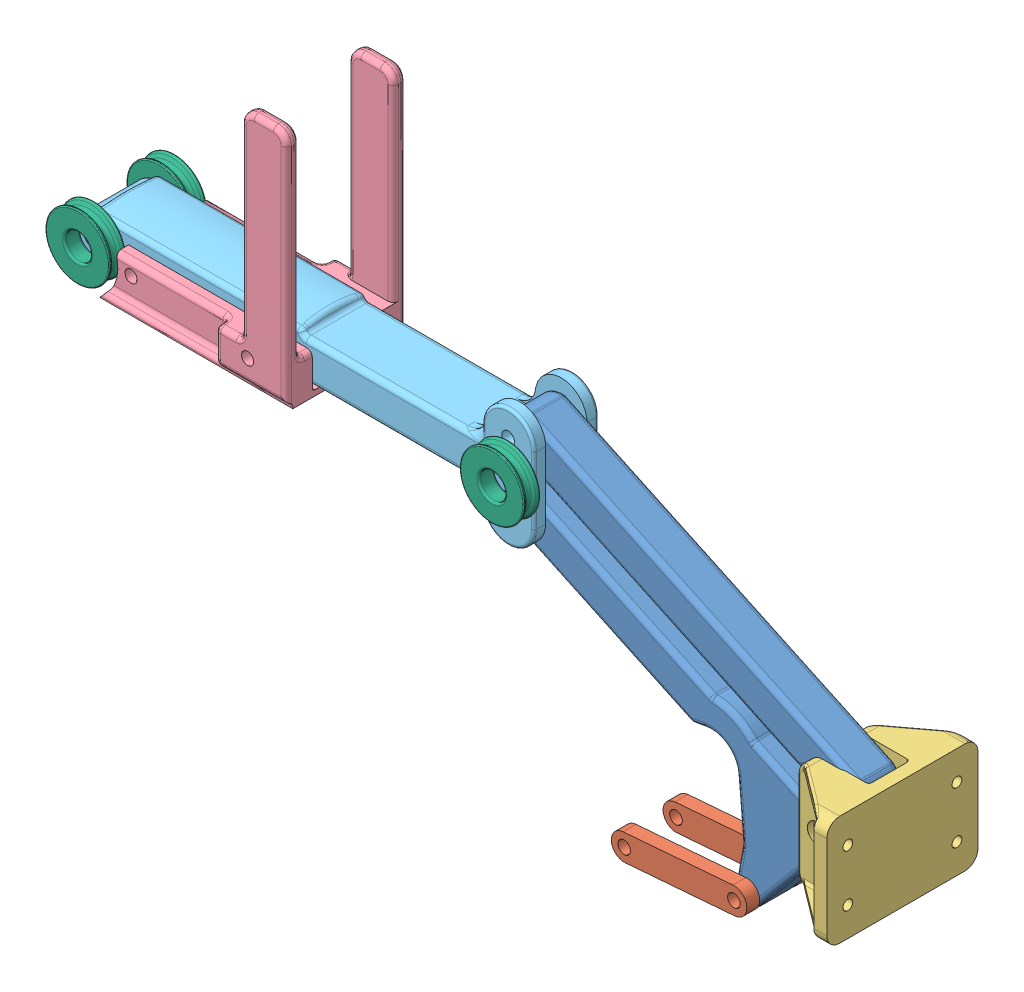
SolidWorks assembly grasper assembly, configuration Default. Lengths in mm.
Overall size (395.8 253.74 74.17).
11 component instances, 7 part files, 34 mates.
Components (placement in the parent):
- arm link-2: arm link [5] at (-109.0843 168.5123 1.2065) x (-0.905616 0.424098 0) z (0 0 -1) size (197.05 24.13 19.05)
- arm link-3: arm link [Default] at (-109.0843 135.4923 0.5715) x (-0.905616 0.424098 0) z (0 0 1) size (197.05 71.69 19.05)
- link driver-2: link driver [Default] at (-105.7742 63.1 13.2715) x (0.996822 0.079659 0) z (0 0 1) size (66.67 12.7 6.35)
- Mounting Bracket-1: Mounting Bracket [Default] at (-12.7 141.2875 0) x (0 0 1) z (0 -1 0) size (74.17 34.92 53.98)
- link driver-3: link driver [Default] at (-105.7742 63.1 -12.1285) x (0.996822 0.079659 0) z (0 0 1) size (66.67 12.7 6.35)
- gutter-1: gutter [Default] at (-303.8936 189.7046 -22.4155) x (-1 0 0) z (0 0 1) size (94.64 118.27 58.79)
- Plate Holder-1: Plate Holder [Default] at (-373.7436 180.1796 17.3169) size (85.72 114.3 6.35) (hidden)
- Contact Arm-2: Contact Arm [Default] at (-189.5936 173.1946 16.4465) x (-1 0 0) z (0 0 -1) size (225.43 58.42 31.75)
- End Pulley-1: End Pulley [Default] at (-392.7936 189.7046 20.4465) size (31.4 31.4 8)
- End Pulley-2: End Pulley [Default] at (-392.7936 189.7046 -19.3035) size (31.4 31.4 8)
- End Pulley-3: End Pulley [Default] at (-189.5936 189.7046 20.4465) x (0.954377 0.298605 0) z (0 0 1) size (31.4 31.4 8)
Mates (geometry in assembly coordinates):
- Coincident5: coincident: plane of ? through (0 0 0) normal (1 0 0); plane of assembly through (0 0 0) normal (1 0 0)
- Coincident6: coincident: plane of ? through (0 0 0) normal (0 1 0); plane of assembly through (0 0 0) normal (0 1 0)
- Coincident7: coincident: plane of ? through (0 0 0) normal (0 0 1); plane of assembly through (0 0 0) normal (0 0 1)
- Coincident8: coincident: point of ?; line of ? through (27.94 13.97 0) axis (0 -1 0)
- Concentric5: concentric: cylinder of ? through (-12.7 0 0) axis (1 0 0) radius 6.35; cylinder of ? through (-140.462 0 0) axis (-1 0 0) radius 6.35
- Coincident12: coincident: plane of ? through (-12.7 0 0) normal (-1 0 0); plane of ? through (-12.7 0 0) normal (1 0 0)
- Distance5: distance = 50.8 mm: sphere of ?; plane of ? through (-153.162 0 0) normal (-1 0 0)
- Distance8: distance = 63.5 mm: cylinder of link driver-2 through (-134.2367 63.5 16.4465) axis (0 0 -1) radius 3.1115; line of ? through (27.94 13.97 0) axis (0 -1 0)
- Coincident25: coincident: plane of ? through (-12.7 0 0) normal (-1 0 0); plane of Mounting Bracket-1 through (-12.7 87.3125 -37.084) normal (1 0 0)
- Coincident26: coincident: plane of ? through (0 0 0) normal (0 0 1); plane of Mounting Bracket-1 through (-12.7 141.2875 0) normal (0 0 1)
- Distance9: distance = 114.3 mm: cylinder of Mounting Bracket-1 through (-38.1 114.3 37.084) axis (0 0 -1) radius 3.9688; cylinder of ? through (-12.7 0 0) axis (1 0 0) radius 6.35
- Concentric16: concentric: cylinder of arm link-3 through (-28.575 97.79 10.0965) axis (0 0 -1) radius 3.1115; cylinder of Mounting Bracket-1 through (-28.575 97.79 37.084) axis (0 0 -1) radius 3.175
- Coincident27: coincident: plane of arm link-3 through (-109.0843 135.4923 10.0965) normal (0 0 1); plane of Mounting Bracket-1 through (-47.625 87.3125 10.0965) normal (0 0 -1)
- Concentric19: concentric: cylinder of link driver-2 through (-78.8725 65.2498 16.4465) axis (0 0 -1) radius 3.1115; cylinder of arm link-3 through (-78.8725 65.2498 10.0965) axis (0 0 -1) radius 3.1115
- Coincident29: coincident: plane of arm link-3 through (-109.0843 135.4923 10.0965) normal (0 0 1); plane of link driver-2 through (-132.676 60.9502 10.0965) normal (0 0 -1)
- Concentric22: concentric: cylinder of link driver-3 through (-78.8725 65.2498 -8.9535) axis (0 0 -1) radius 3.1115; cylinder of arm link-3 through (-78.8725 65.2498 10.0965) axis (0 0 -1) radius 3.1115
- Coincident31: coincident: plane of arm link-3 through (-109.0843 135.4923 -8.9535) normal (0 0 -1); plane of link driver-3 through (-132.676 60.9502 -8.9535) normal (0 0 1)
- Concentric23: concentric: cylinder of link driver-2 through (-132.676 60.9502 16.4465) axis (0 0 -1) radius 3.1115; cylinder of link driver-3 through (-132.676 60.9502 -8.9535) axis (0 0 -1) radius 3.1115
- Concentric30: concentric: cylinder of arm link-3 through (-189.5936 173.1946 10.0965) axis (0 0 -1) radius 3.1115; cylinder of Contact Arm-2 through (-189.5936 173.1946 -15.3035) axis (0 0 1) radius 3.1115
- Width1: width: plane of Contact Arm-2 through (-202.2936 173.1946 10.7315) normal (0 0 -1); plane of Contact Arm-2 through (-202.2936 173.1946 -9.5885) normal (0 0 1); plane of arm link-3 through (-109.0843 135.4923 10.0965) normal (0 0 1); plane of arm link-3 through (-109.0843 135.4923 -8.9535) normal (0 0 -1)
- Concentric32: concentric: cylinder of Plate Holder-1 through (-367.3936 189.7046 23.6669) axis (0 0 -1) radius 3.175; cylinder of Contact Arm-2 through (-367.3936 189.7046 16.4465) axis (0 0 -1) radius 3.1115
- Concentric33: concentric: cylinder of Plate Holder-1 through (-303.8936 189.7046 23.6669) axis (0 0 -1) radius 3.175; cylinder of Contact Arm-2 through (-303.8936 189.7046 16.4465) axis (0 0 -1) radius 3.1115
- Concentric34: concentric: cylinder of gutter-1 through (-303.8936 189.7046 23.5585) axis (0 0 -1) radius 3.048; cylinder of Contact Arm-2 through (-303.8936 189.7046 16.4465) axis (0 0 -1) radius 3.1115
- Concentric35: concentric: cylinder of gutter-1 through (-367.3936 189.7046 23.5585) axis (0 0 -1) radius 3.048; cylinder of Contact Arm-2 through (-367.3936 189.7046 16.4465) axis (0 0 -1) radius 3.1115
- Width3: width: plane of gutter-1 through (-379.5238 189.7046 -16.0655) normal (0 0 1); plane of gutter-1 through (-379.5238 189.7046 17.2085) normal (0 0 -1); plane of Contact Arm-2 through (-189.5936 173.1946 -15.3035) normal (0 0 -1); plane of Contact Arm-2 through (-189.5936 173.1946 16.4465) normal (0 0 1)
- Concentric36: concentric: cylinder of Contact Arm-2 through (-392.7936 189.7046 13.2715) axis (0 0 1) radius 4.7625; cylinder of End Pulley-1 through (-392.7936 189.7046 16.4465) axis (0 0 1) radius 6.35
- Coincident35: coincident: plane of Contact Arm-2 through (-189.5936 173.1946 16.4465) normal (0 0 1); plane of End Pulley-1 through (-392.7936 189.7046 16.4465) normal (0 0 -1)
- Concentric37: concentric: cylinder of Contact Arm-2 through (-392.7936 189.7046 -12.1285) axis (0 0 -1) radius 4.7625; cylinder of End Pulley-2 through (-392.7936 189.7046 -23.3035) axis (0 0 1) radius 6.35
- Coincident36: coincident: plane of Contact Arm-2 through (-189.5936 173.1946 -15.3035) normal (0 0 -1); plane of End Pulley-2 through (-392.7936 189.7046 -15.3035) normal (0 0 1)
- Concentric38: concentric: cylinder of Contact Arm-2 through (-189.5936 189.7046 -15.3035) axis (0 0 1) radius 3.1115; cylinder of End Pulley-3 through (-189.5936 189.7046 16.4465) axis (0 0 1) radius 6.35
- Coincident37: coincident: plane of Contact Arm-2 through (-189.5936 173.1946 16.4465) normal (0 0 1); plane of End Pulley-3 through (-189.5936 189.7046 16.4465) normal (0 0 -1)
- Concentric39: concentric: cylinder of arm link-2 through (-28.575 130.81 -8.3185) axis (0 0 1) radius 3.1115; cylinder of Mounting Bracket-1 through (-28.575 130.81 37.084) axis (0 0 -1) radius 3.175
- Concentric40: concentric: cylinder of arm link-2 through (-189.5936 206.2146 -8.3185) axis (0 0 1) radius 3.1115; cylinder of Contact Arm-2 through (-189.5936 206.2146 -15.3035) axis (0 0 1) radius 3.1115
- Coincident38: coincident: plane of arm link-2 through (-109.0843 168.5123 10.7315) normal (0 0 1); plane of Contact Arm-2 through (-202.2936 173.1946 10.7315) normal (0 0 -1)
